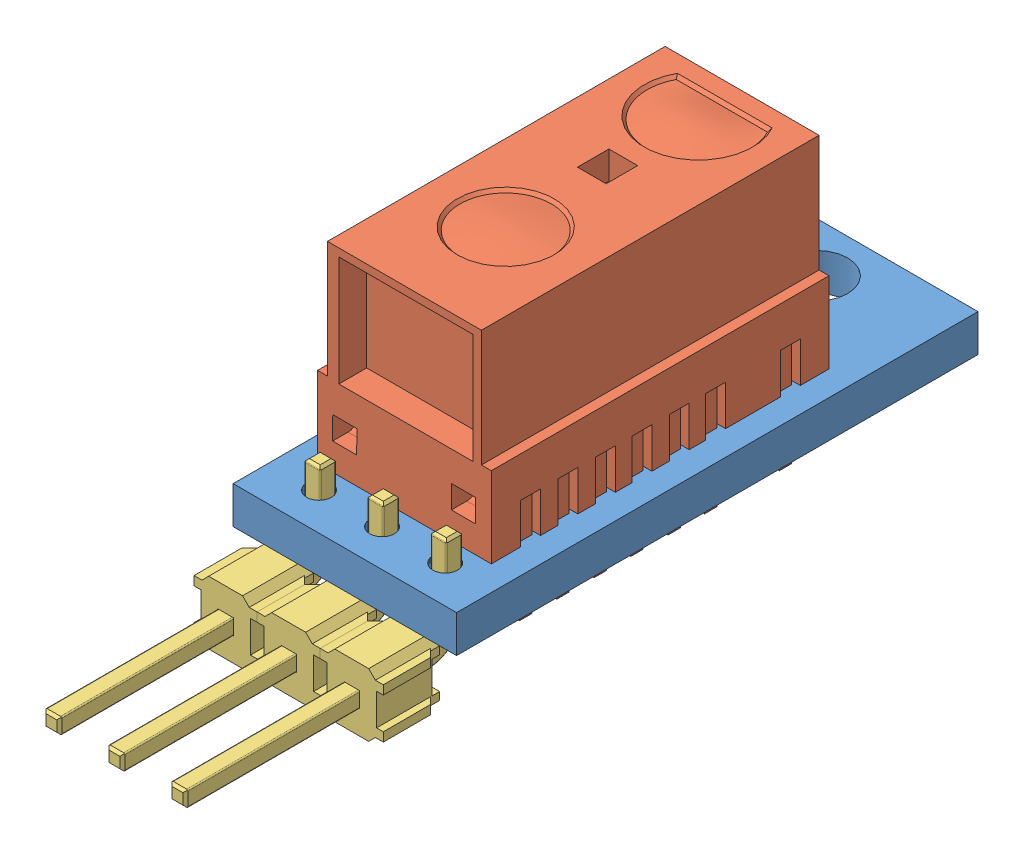
SolidWorks assembly SensorSharpDigital, configuration Predeterminado. Lengths in mm.
Overall size (105.72 12.08 264.56).
3 component instances, 3 part files, 7 mates.
Components (placement in the parent):
- Base-1: Base [Predeterminado] at (-0.1111 -0.2083 21) size (9 1.5 21)
- GP2Y0D810Z0F sharp-1: GP2Y0D810Z0F sharp [Default] at (-0.1307 1.2917 20.694) x (0 0 1) z (0 1 0) size (252.38 104.72 10.79)
- PIN3Angulo-1: PIN3Angulo [Predeterminado] at (2.3889 -1.4783 31.1825) x (-1 0 0) z (0 1 0) size (7.75 13.2 5.08)
Mates (geometry in assembly coordinates):
- Coincidente3: coincident anti-aligned: plane of Base-1 through (-0.1111 1.2917 21) normal (0 1 0); plane of GP2Y0D810Z0F sharp-1 through (-0.1307 1.2917 20.694) normal (0 -1 0)
- Paralelo2: parallel aligned: line of Base-1 through (-4.6111 1.2917 31.5) axis (1 0 0); line of GP2Y0D810Z0F sharp-1 through (-3.6111 1.2917 29.1) axis (1 0 0)
- Distancia4: distance = 1 mm: line of GP2Y0D810Z0F sharp-1 through (-3.6111 1.2917 17.4559) axis (0 0 1); line of Base-1 through (-4.6111 1.2917 10.5) axis (0 0 1)
- Distancia5: distance = 5 mm: line of GP2Y0D810Z0F sharp-1 through (3.3889 1.2917 15.5) axis (-1 0 0); line of Base-1 through (4.3889 1.2917 10.5) axis (-1 0 0)
- Coincidente13: coincident anti-aligned: plane of Base-1 through (-0.1111 -0.2083 21) normal (0 -1 0); plane of PIN3Angulo-1 through (-1.1511 -0.2083 33.7225) normal (0 1 0)
- Coincidente14: coincident anti-aligned: line of Base-1 through (-4.6111 -0.2083 31.5) axis (1 0 0); line of PIN3Angulo-1 through (0.4889 -0.2083 31.5) axis (-1 0 0)
- Distancia9: distance = 1 mm aligned: plane of PIN3Angulo-1 through (3.3889 -2.4783 33.7225) normal (1 0 0); plane of Base-1 through (4.3889 1.2917 31.5) normal (1 0 0)
